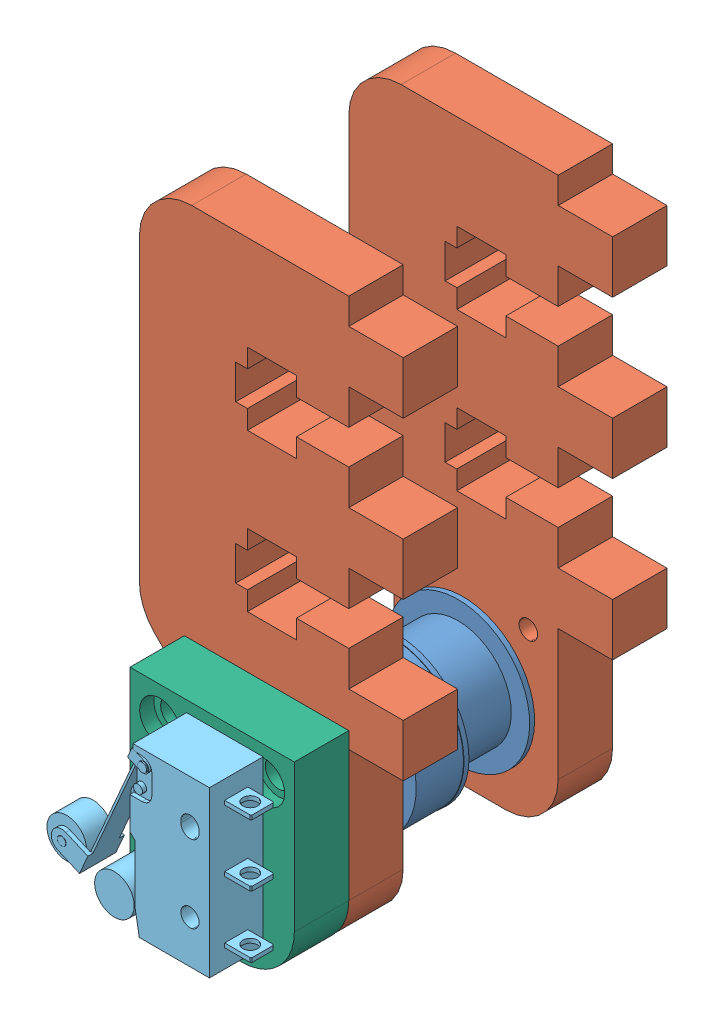
SolidWorks assembly PULLEY BLOCK, INFEED, configuration Default. Lengths in mm.
Overall size (32 69.85 45.11).
8 component instances, 6 part files, 20 mates.
Components (placement in the parent):
- 1375K39-1: 1375K39 [Default] at (-9.9695 -57.15 1.5875) x (0.936479 0.350722 0) z (0.350722 -0.936479 0) size (17.4 14.3 17.4)
- MOUNT, PULLY-1: MOUNT, PULLY [Default] x (1 0 0) z (0 0 -1) size (32 69.85 6.6)
- MOUNT, PULLY-2: MOUNT, PULLY [Default] at (0 0 25.4) x (1 0 0) z (0 0 -1) size (32 69.85 6.6)
- 6338K411-1: 6338K411 [Default] at (-9.9695 -57.15 -6.35) x (-0.837169 -0.546944 0) z (-0.546944 0.837169 0) size (12.7 7.94 12.7)
- 6338K411-2: 6338K411 [Default] at (-9.9695 -57.15 25.146) x (0.871903 0.489679 0) z (-0.489679 0.871903 0) size (12.7 7.94 12.7)
- SHAFT, PULLY-1: SHAFT, PULLY [Default] at (-9.9695 -57.15 25.4) x (0.462626 0.886554 0) z (0 0 -1) size (6.35 6.35 31.75)
- 7658K160-1: 7658K160 [Default] at (-3.7973 -56.9849 35.2552) x (0 -1 0) z (0 0 -1) size (21.02 24.56 6.5)
- LIMIT SWITCH MOUNT, INFEED-1: LIMIT SWITCH MOUNT, INFEED [Default] at (-9.9695 -45.6438 32.004) x (1 0 0) z (0 1 0) size (19.94 6.6 24.21)
Mates (geometry in assembly coordinates):
- Concentric1: concentric aligned: cylinder of 1375K39-1 through (-9.9695 -57.15 28.2701) axis (0 0 1) radius 3.175; cylinder of MOUNT, PULLY-1 through (-9.9695 -57.15 -6.604) axis (0 0 1) radius 4.7625
- Concentric2: concentric aligned: cylinder of MOUNT, PULLY-1 through (-9.9695 -57.15 -6.604) axis (0 0 1) radius 4.7625; cylinder of MOUNT, PULLY-2 through (-9.9695 -57.15 18.796) axis (0 0 1) radius 4.7625
- Concentric3: concentric aligned: cylinder of MOUNT, PULLY-2 through (-9.9695 -57.15 18.796) axis (0 0 1) radius 4.7625; cylinder of 6338K411-2 through (-9.9695 -57.15 25.146) axis (0 0 1) radius 4.7625
- Concentric4: concentric anti-aligned: cylinder of MOUNT, PULLY-1 through (-9.9695 -57.15 -6.604) axis (0 0 1) radius 4.7625; cylinder of 6338K411-1 through (-9.9695 -57.15 -6.35) axis (0 0 -1) radius 4.7625
- Coincident3: coincident anti-aligned: plane of MOUNT, PULLY-1 through (0 0 0) normal (0 0 1); plane of 6338K411-1 through (-6.4964 -62.466 0) normal (0 0 -1)
- Coincident4: coincident aligned: plane of MOUNT, PULLY-1 through (-25.4 0 -6.604) normal (-1 0 0); plane of MOUNT, PULLY-2 through (-25.4 0 18.796) normal (-1 0 0)
- Coincident5: coincident anti-aligned: plane of MOUNT, PULLY-2 through (0 0 18.796) normal (0 0 -1); plane of 6338K411-2 through (-6.86 -62.6866 18.796) normal (0 0 1)
- Distance1: distance = 25.4 mm aligned: plane of MOUNT, PULLY-1 through (0 0 -6.604) normal (0 0 -1); plane of MOUNT, PULLY-2 through (0 0 18.796) normal (0 0 -1)
- Concentric5: concentric anti-aligned: cylinder of 6338K411-1 through (-9.9695 -57.15 -6.35) axis (0 0 -1) radius 3.175; cylinder of SHAFT, PULLY-1 through (-9.9695 -57.15 -6.35) axis (0 0 1) radius 3.175
- Coincident8: coincident aligned: plane of MOUNT, PULLY-2 through (0 0 25.4) normal (0 0 1); plane of SHAFT, PULLY-1 through (-9.9695 -57.15 25.4) normal (0 0 1)
- Coincident11: coincident anti-aligned: plane of MOUNT, PULLY-1 through (0 0 0) normal (0 0 -1); plane of assembly through (0 0 0) normal (0 0 1)
- Coincident12: coincident anti-aligned: plane of MOUNT, PULLY-1 through (0 0 0) normal (0 -1 0); plane of assembly through (0 0 0) normal (0 1 0)
- Coincident13: coincident aligned: plane of MOUNT, PULLY-1; plane of assembly through (0 0 0) normal (1 0 0)
- Concentric6: concentric anti-aligned: cylinder of 7658K160-1 through (-6.1595 -61.7728 32.004) axis (0 0 1) radius 1.1049; cylinder of LIMIT SWITCH MOUNT, INFEED-1 through (-6.1595 -61.7728 25.4) axis (0 0 -1) radius 1.1303
- Coincident14: coincident anti-aligned: plane of MOUNT, PULLY-2 through (0 0 25.4) normal (0 0 1); plane of LIMIT SWITCH MOUNT, INFEED-1 through (-9.9695 -45.6438 25.4) normal (0 0 -1)
- Coincident15: coincident anti-aligned: plane of 7658K160-1 through (-3.7973 -66.9798 32.004) normal (0 0 -1); plane of LIMIT SWITCH MOUNT, INFEED-1 through (-9.9695 -45.6438 32.004) normal (0 0 1)
- Parallel2: parallel aligned: plane of 7658K160-1 through (-3.7973 -46.99 32.004) normal (1 0 0); plane of LIMIT SWITCH MOUNT, INFEED-1 through (0 -69.85 25.4) normal (1 0 0)
- Concentric13: concentric anti-aligned: cylinder of MOUNT, PULLY-2 through (-16.3195 -49.53 18.796) axis (0 0 -1) radius 1.1303; cylinder of LIMIT SWITCH MOUNT, INFEED-1 through (-16.3195 -49.53 32.004) axis (0 0 1) radius 1.632
- Concentric14: concentric anti-aligned: cylinder of MOUNT, PULLY-2 through (-3.6195 -49.53 18.796) axis (0 0 -1) radius 1.1303; cylinder of LIMIT SWITCH MOUNT, INFEED-1 through (-3.6195 -49.53 32.004) axis (0 0 1) radius 1.632
- Coincident16: coincident anti-aligned: plane of 1375K39-1 through (-6.9962 -56.0365 1.5875) normal (0 0 -1); plane of 6338K411-1 through (-8.233 -59.808 1.5875) normal (0 0 1)
